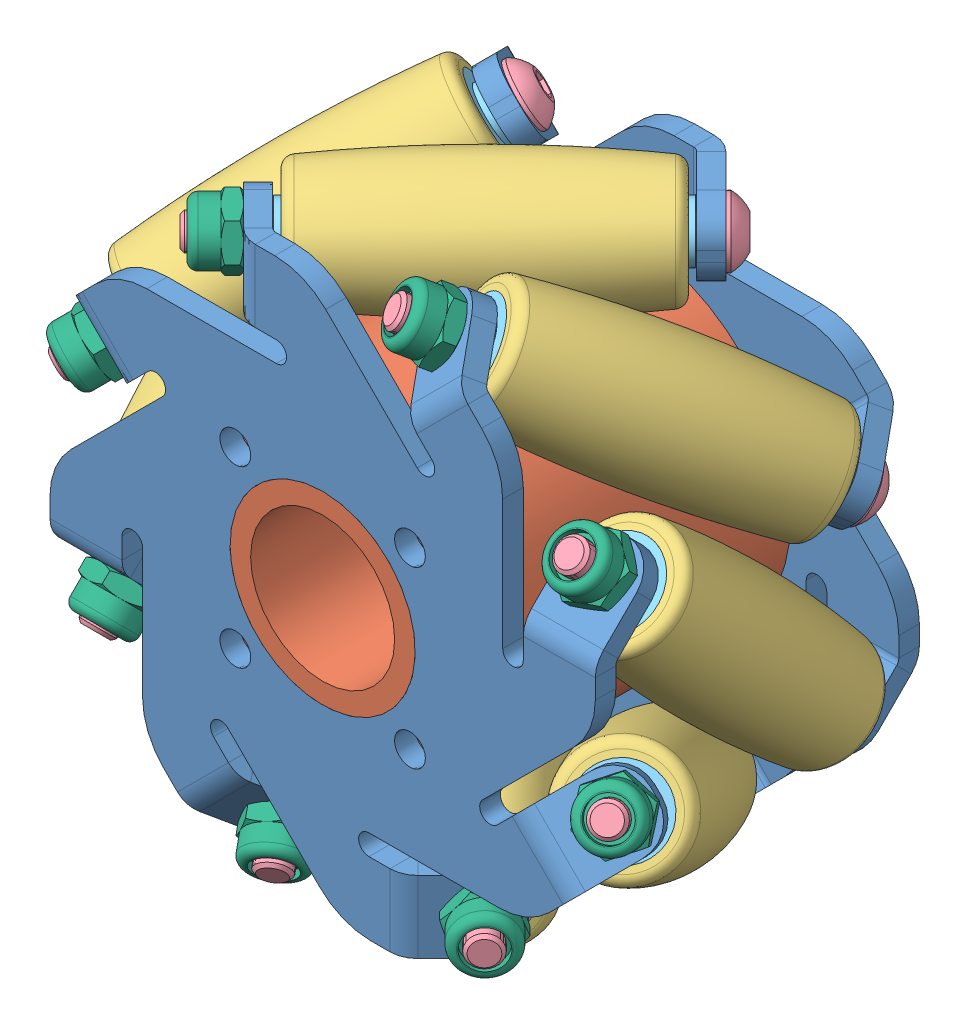
SolidWorks assembly left_mecanum_wheel_assembly, configuration Default. Lengths in mm.
Overall size (63.15 63.15 33.61).
43 component instances, 6 part files, 21 mates.
Components (placement in the parent):
- 60mm_left_mecanum_wheel_frame-1: 60mm_left_mecanum_wheel_frame [Default] at (21.5434 25.3529 14.249) x (0 1 0) z (0 0 -1) size (55.02 55.02 7.58)
- connector-1: connector [Default] at (21.5434 25.3529 -13.251) size (32 32 31.5)
- roller-1: roller [Default] at (-1.4566 25.364 0.5102) x (0 -0.707107 0.707107) z (-0.847066 -0.375818 -0.375818) size (28 12.44 12.44)
- 60mm_left_mecanum_wheel_frame-3: 60mm_left_mecanum_wheel_frame [Default] at (21.5434 25.3529 -13.251) size (55.02 55.02 7.58)
- boult-M3-1: boult-M3 [Default] at (-1.4566 38.2475 -12.3733) x (0 -0.707107 0.707107) z (-0.682394 0.516884 0.516884) size (39.15 5.7 5.7)
- roller_brackets-1: roller_brackets [Default] at (-1.4566 34.2029 -8.3287) x (-0.843987 -0.379267 -0.379267) z (0 0.707107 -0.707107) size (7.5 7.5 2)
- roller_brackets-2: roller_brackets [Default] at (-1.4566 16.5252 9.349) x (0.778678 -0.443656 -0.443656) z (0 -0.707107 0.707107) size (7.5 7.5 2)
- torque nut 08_iso-1: torque nut 08_iso [ISO 10511-M3-N] at (-1.4566 12.529 13.3007) x (0.665798 0.527595 0.527595) z (0 -0.707107 0.707107) size (5.5 6.35 3.9)
- torque nut 08_iso-3: torque nut 08_iso [ISO 10511-M3-N] at (-3.7879 32.5485 13.3007) x (0.843856 -0.097724 0.527595) z (-0.5 -0.5 0.707107) size (5.5 6.35 3.9)
- torque nut 08_iso-4: torque nut 08_iso [ISO 10511-M3-N] at (8.7195 48.3529 13.3007) x (0.527595 -0.665798 0.527595) z (-0.707107 0 0.707107) size (5.5 6.35 3.9)
- torque nut 08_iso-5: torque nut 08_iso [ISO 10511-M3-N] at (28.739 50.6842 13.3007) x (-0.097724 -0.843856 0.527595) z (-0.5 0.5 0.707107) size (5.5 6.35 3.9)
- torque nut 08_iso-6: torque nut 08_iso [ISO 10511-M3-N] at (44.5434 38.1768 13.3007) x (-0.665798 -0.527595 0.527595) z (0 0.707107 0.707107) size (5.5 6.35 3.9)
- torque nut 08_iso-7: torque nut 08_iso [ISO 10511-M3-N] at (46.8748 18.1573 13.3007) x (-0.843856 0.097724 0.527595) z (0.5 0.5 0.707107) size (5.5 6.35 3.9)
- torque nut 08_iso-8: torque nut 08_iso [ISO 10511-M3-N] at (34.3674 2.3529 13.3007) x (-0.527595 0.665798 0.527595) z (0.707107 0 0.707107) size (5.5 6.35 3.9)
- torque nut 08_iso-9: torque nut 08_iso [ISO 10511-M3-N] at (14.3479 0.0215 13.3007) x (0.097724 0.843856 0.527595) z (0.5 -0.5 0.707107) size (5.5 6.35 3.9)
- roller_brackets-3: roller_brackets [Default] at (-0.9621 35.3742 9.349) x (0.236897 -0.86432 -0.443656) z (-0.5 -0.5 0.707107) size (7.5 7.5 2)
- roller_brackets-4: roller_brackets [Default] at (12.7158 48.3529 9.349) x (-0.443656 -0.778678 -0.443656) z (-0.707107 0 0.707107) size (7.5 7.5 2)
- roller_brackets-5: roller_brackets [Default] at (31.5648 47.8585 9.349) x (-0.86432 -0.236897 -0.443656) z (-0.5 0.5 0.707107) size (7.5 7.5 2)
- roller_brackets-6: roller_brackets [Default] at (44.5434 34.1806 9.349) x (-0.778678 0.443656 -0.443656) z (0 0.707107 0.707107) size (7.5 7.5 2)
- roller_brackets-7: roller_brackets [Default] at (44.049 15.3315 9.349) x (-0.236897 0.86432 -0.443656) z (0.5 0.5 0.707107) size (7.5 7.5 2)
- roller_brackets-8: roller_brackets [Default] at (30.3711 2.3529 9.349) x (0.443656 0.778678 -0.443656) z (0.707107 0 0.707107) size (7.5 7.5 2)
- roller_brackets-9: roller_brackets [Default] at (11.5221 2.8473 9.349) x (0.86432 0.236897 -0.443656) z (0.5 -0.5 0.707107) size (7.5 7.5 2)
- roller_brackets-10: roller_brackets [Default] at (11.5379 47.8742 -8.3287) x (-0.864971 0.328607 -0.379267) z (0.5 0.5 -0.707107) size (7.5 7.5 2)
- roller_brackets-11: roller_brackets [Default] at (30.3934 48.3529 -8.3287) x (-0.379267 0.843987 -0.379267) z (0.707107 0 -0.707107) size (7.5 7.5 2)
- roller_brackets-12: roller_brackets [Default] at (44.0648 35.3585 -8.3287) x (0.328607 0.864971 -0.379267) z (0.5 -0.5 -0.707107) size (7.5 7.5 2)
- roller_brackets-13: roller_brackets [Default] at (44.5434 16.5029 -8.3287) x (0.843987 0.379267 -0.379267) z (0 -0.707107 -0.707107) size (7.5 7.5 2)
- roller_brackets-14: roller_brackets [Default] at (31.549 2.8315 -8.3287) x (0.864971 -0.328607 -0.379267) z (-0.5 -0.5 -0.707107) size (7.5 7.5 2)
- roller_brackets-15: roller_brackets [Default] at (12.6935 2.3529 -8.3287) x (0.379267 -0.843987 -0.379267) z (-0.707107 0 -0.707107) size (7.5 7.5 2)
- roller_brackets-16: roller_brackets [Default] at (-0.9779 15.3473 -8.3287) x (-0.328607 -0.864971 -0.379267) z (-0.5 0.5 -0.707107) size (7.5 7.5 2)
- roller-23: roller [Default] at (5.2879 41.6242 0.5102) x (-0.5 -0.5 0.707107) z (-0.86471 0.333223 -0.375818) size (28 12.44 12.44)
- roller-24: roller [Default] at (21.5546 48.3529 0.5102) x (-0.707107 0 0.707107) z (-0.375818 0.847066 -0.375818) size (28 12.44 12.44)
- roller-25: roller [Default] at (37.8148 41.6085 0.5102) x (-0.5 0.5 0.707107) z (0.333223 0.86471 -0.375818) size (28 12.44 12.44)
- roller-26: roller [Default] at (44.5434 25.3417 0.5102) x (0 0.707107 0.707107) z (0.847066 0.375818 -0.375818) size (28 12.44 12.44)
- roller-27: roller [Default] at (37.799 9.0815 0.5102) x (0.5 0.5 0.707107) z (0.86471 -0.333223 -0.375818) size (28 12.44 12.44)
- roller-28: roller [Default] at (21.5323 2.3529 0.5102) x (0.707107 0 0.707107) z (0.375818 -0.847066 -0.375818) size (28 12.44 12.44)
- roller-29: roller [Default] at (5.2721 9.0973 0.5102) x (0.5 -0.5 0.707107) z (-0.333223 -0.86471 -0.375818) size (28 12.44 12.44)
- boult-M3-2: boult-M3 [Default] at (14.3979 50.7342 -12.3733) x (-0.5 -0.5 0.707107) z (-0.117033 0.848018 0.516884) size (39.15 5.7 5.7)
- boult-M3-3: boult-M3 [Default] at (34.4381 48.3529 -12.3733) x (-0.707107 0 0.707107) z (0.516884 0.682394 0.516884) size (39.15 5.7 5.7)
- boult-M3-4: boult-M3 [Default] at (46.9248 32.4985 -12.3733) x (-0.5 0.5 0.707107) z (0.848018 0.117033 0.516884) size (39.15 5.7 5.7)
- boult-M3-5: boult-M3 [Default] at (44.5434 12.4582 -12.3733) x (0 0.707107 0.707107) z (0.682394 -0.516884 0.516884) size (39.15 5.7 5.7)
- boult-M3-6: boult-M3 [Default] at (28.689 -0.0285 -12.3733) x (0.5 0.5 0.707107) z (0.117033 -0.848018 0.516884) size (39.15 5.7 5.7)
- boult-M3-7: boult-M3 [Default] at (8.6488 2.3529 -12.3733) x (0.707107 0 0.707107) z (-0.516884 -0.682394 0.516884) size (39.15 5.7 5.7)
- boult-M3-8: boult-M3 [Default] at (-3.8379 18.2073 -12.3733) x (0.5 -0.5 0.707107) z (-0.848018 -0.117033 0.516884) size (39.15 5.7 5.7)
Mates (geometry in assembly coordinates):
- Concentric8: concentric anti-aligned: cylinder of connector-1 through (21.5434 25.3529 14.249) axis (0 0 -1) radius 7; cylinder of 60mm_left_mecanum_wheel_frame-3 through (21.5434 25.3529 -15.251) axis (0 0 1) radius 9
- Coincident15: coincident anti-aligned: plane of connector-1 through (21.5434 25.3529 -13.251) normal (0 0 -1); plane of 60mm_left_mecanum_wheel_frame-3 through (34.0434 47.8529 -13.251) normal (0 0 1)
- Concentric9: concentric anti-aligned: cylinder of connector-1 through (30.0287 33.8382 14.249) axis (0 0 -1) radius 1.5; cylinder of 60mm_left_mecanum_wheel_frame-3 through (30.0287 33.8382 -15.251) axis (0 0 1) radius 1.5
- Concentric10: concentric aligned: cylinder of 60mm_left_mecanum_wheel_frame-1 through (21.5434 25.3529 16.249) axis (0 0 -1) radius 9; cylinder of connector-1 through (21.5434 25.3529 14.249) axis (0 0 -1) radius 7
- Coincident16: coincident anti-aligned: plane of 60mm_left_mecanum_wheel_frame-1 through (44.0434 37.8529 14.249) normal (0 0 -1); plane of connector-1 through (21.5434 25.3529 14.249) normal (0 0 1)
- Concentric11: concentric aligned: cylinder of 60mm_left_mecanum_wheel_frame-1 through (30.0287 16.8676 16.249) axis (0 0 -1) radius 1.5; cylinder of connector-1 through (30.0287 16.8676 14.249) axis (0 0 -1) radius 1.5
- Concentric12: concentric anti-aligned: cylinder of roller-1 through (-1.4566 78.397 -52.5228) axis (0 0.707107 -0.707107) radius 1.5; cylinder of roller_brackets-1 through (-1.4566 35.6171 -9.7429) axis (0 -0.707107 0.707107) radius 1.5
- Coincident17: coincident anti-aligned: plane of roller-1 through (-2.2538 35.1013 -7.4302) normal (0 0.707107 -0.707107); plane of roller_brackets-1 through (-1.4566 34.2029 -8.3287) normal (0 -0.707107 0.707107)
- Concentric13: concentric aligned: cylinder of roller-1 through (-1.4566 78.397 -52.5228) axis (0 0.707107 -0.707107) radius 1.5; cylinder of roller_brackets-2 through (-1.4566 15.111 10.7632) axis (0 0.707107 -0.707107) radius 1.5
- Coincident18: coincident anti-aligned: plane of roller-1 through (-2.2538 17.4236 10.2474) normal (0 -0.707107 0.707107); plane of roller_brackets-2 through (-1.4566 16.5252 9.349) normal (0 0.707107 -0.707107)
- Concentric14: concentric anti-aligned: cylinder of roller-1 through (-1.4566 78.397 -52.5228) axis (0 0.707107 -0.707107) radius 1.5; cylinder of 60mm_left_mecanum_wheel_frame-3 through (-1.4566 37.0808 -11.2066) axis (0 -0.707107 0.707107) radius 1.5
- Concentric15: concentric anti-aligned: cylinder of 60mm_left_mecanum_wheel_frame-3 through (-1.4566 37.0808 -11.2066) axis (0 -0.707107 0.707107) radius 1.5; cylinder of boult-M3-1 through (-1.4566 38.2475 -12.3733) axis (0 0.707107 -0.707107) radius 1.5
- Coincident19: coincident anti-aligned: plane of 60mm_left_mecanum_wheel_frame-3 through (34.0434 44.1519 -4.1355) normal (0 0.707107 -0.707107); plane of boult-M3-1 through (-0.3601 37.8046 -10.4828) normal (0 -0.707107 0.707107)
- Width4: width anti-aligned: plane of roller_brackets-1 through (-1.4566 35.6171 -9.7429) normal (0 0.707107 -0.707107); plane of 60mm_left_mecanum_wheel_frame-3 through (-1.4566 15.111 10.7632) normal (0 -0.707107 0.707107); plane of roller_brackets-2 through (34.0434 42.7377 -2.7213) normal (0 -0.707107 0.707107); plane of 60mm_left_mecanum_wheel_frame-1 through (44.0434 32.7169 28.4681) normal (0 0.707107 -0.707107)
- Concentric16: concentric aligned: cylinder of boult-M3-1 through (-1.4566 38.2475 -12.3733) axis (0 0.707107 -0.707107) radius 1.5; cylinder of prevailing torque hex nut_am-1 through (-1.4566 -4.2978 30.172) axis (0 0.707107 -0.707107) radius 1.5
- Coincident20: coincident: plane of prevailing torque hex nut_am-1 through (-4.2066 10.0917 13.5371) normal (-1 0 0); plane of prevailing torque hex nut_am-2 through (-4.2066 15.1914 14.0965) normal (1 0 0)
- Concentric19: concentric aligned: cylinder of boult-M3-1 through (-1.4566 38.2475 -12.3733) axis (0 0.707107 -0.707107) radius 1.5; cylinder of hex nut style 2_am-1 through (-1.4566 -5.2714 31.1456) axis (0 0.707107 -0.707107) radius 1.5
- Coincident21: coincident anti-aligned: plane of 60mm_left_mecanum_wheel_frame-1 through (44.0434 31.3026 29.8823) normal (0 -0.707107 0.707107); plane of hex nut style 2_am-1 through (-1.5733 11.4034 9.9831) normal (0 0.707107 -0.707107)
- Concentric20: concentric anti-aligned: cylinder of 60mm_left_mecanum_wheel_frame-1 through (-1.4566 13.625 12.2046) axis (0 0.707107 -0.707107) radius 1.5; cylinder of torque nut 08_iso-1 through (-1.4566 -0.9414 26.771) axis (0 -0.707107 0.707107) radius 1.5
- Coincident22: coincident anti-aligned: plane of 60mm_left_mecanum_wheel_frame-1 through (44.0434 31.3026 29.8823) normal (0 -0.707107 0.707107); plane of torque nut 08_iso-1 through (-3.8258 15.1199 13.6996) normal (0 0.707107 -0.707107)
- Concentric21: concentric aligned: cylinder of torque nut 08_iso-1 through (-1.4566 5.825 20.0047) axis (0 -0.707107 0.707107) radius 2.75; cylinder of torque nut 08_iso-2 through (-1.4566 -1.377 27.2066) axis (0 -0.707107 0.707107) radius 1.5
